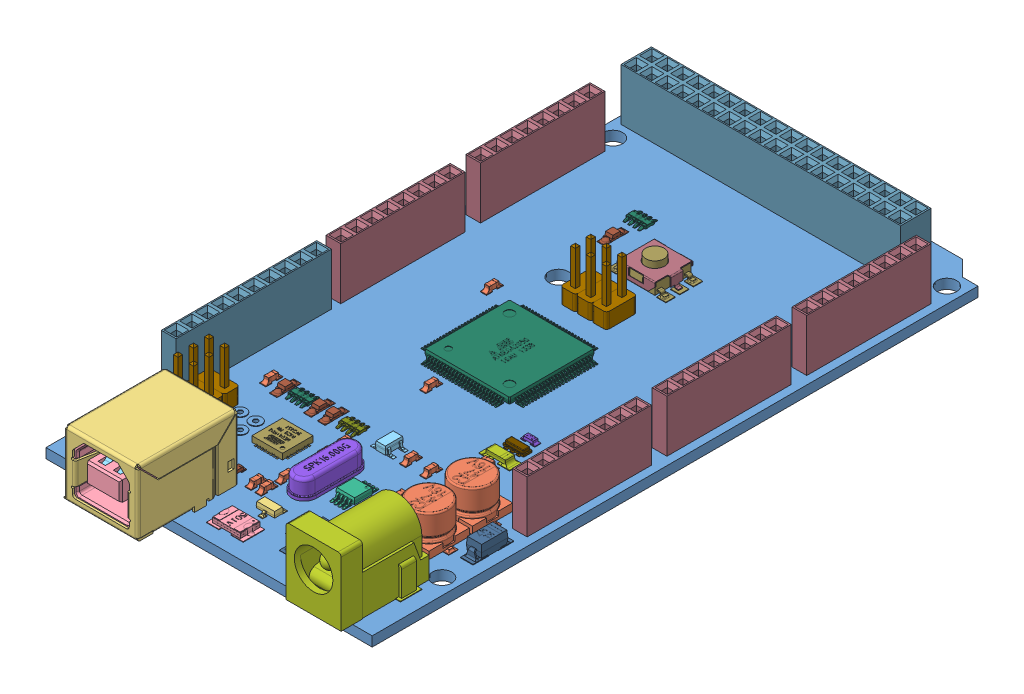
SolidWorks assembly User Library-arduino_MEGA2650-1, configuration Default. Lengths in mm.
Overall size (53.34 15.25 107.95).
67 component instances, 33 part files, 0 mates.
Components (placement in the parent):
- User Library-arduino_MEGA2650-1_MEGAboard-1: User Library-arduino_MEGA2650-1_MEGAboard [Default] at origin size (53.34 1.6 101.6)
- User Library-arduino_MEGA2650-1_47uf CAP Dcase-1: User Library-arduino_MEGA2650-1_47uf CAP Dcase [Default] at (-9.144 0 -18.415) x (0 0 -1) z (1 0 0) size (6.6 5.81 8)
- User Library-arduino_MEGA2650-1_USB SHELL-1: User Library-arduino_MEGA2650-1_USB SHELL [Default] at (-38.02 0.43 6.35) size (13.72 15.2 16.51)
- User Library-arduino_MEGA2650-1_USB core-1: User Library-arduino_MEGA2650-1_USB core [Default] at (-38.02 0.43 6.35) size (11.3 10.68 15.75)
- User Library-arduino_MEGA2650-1_usb top contact-1: User Library-arduino_MEGA2650-1_usb top contact [Default] at (-36.77 6.52 5.97) size (1 9.67 13.76)
- User Library-arduino_MEGA2650-1_usb btm contact-1: User Library-arduino_MEGA2650-1_usb btm contact [Default] at (-36.77 4.84 5.97) size (1 6.84 11.76)
- User Library-arduino_MEGA2650-1_usb btm contact-2: User Library-arduino_MEGA2650-1_usb btm contact [Default] at (-39.27 4.84 5.97) size (1 6.84 11.76)
- User Library-arduino_MEGA2650-1_usb top contact-2: User Library-arduino_MEGA2650-1_usb top contact [Default] at (-39.27 6.52 5.97) size (1 9.67 13.76)
- User Library-arduino_MEGA2650-1_power jack-1: User Library-arduino_MEGA2650-1_power jack [Default] at (-7.675 0 1.905) size (11.2 15.2 15.9)
- User Library-arduino_MEGA2650-1_47uf CAP Dcase-2: User Library-arduino_MEGA2650-1_47uf CAP Dcase [Default] at (-9.144 0 -25.527) x (0 0 -1) z (1 0 0) size (6.6 5.81 8)
- User Library-arduino_MEGA2650-1_crystal-1: User Library-arduino_MEGA2650-1_crystal [Default] at (-26.035 0 -18.415) x (1 0 0) z (0 0 -1) size (4 5 11)
- User Library-arduino_MEGA2650-1_2pin_header__02-1: User Library-arduino_MEGA2650-1_2pin_header__02 [Default] at (-46.23 0 -15.75) size (5 11.75 2.54)
- User Library-arduino_MEGA2650-1_reg-1: User Library-arduino_MEGA2650-1_reg [Default] at (-17.78 0 -8.636) size (6.5 1.69 8.3)
- User Library-arduino_MEGA2650-1_led-1: User Library-arduino_MEGA2650-1_led [Default] at (-34.29 0 -27.94) x (0 0 1) z (-1 0 0) size (4 0.9 1.55)
- User Library-arduino_MEGA2650-1_2pin_header__02-2: User Library-arduino_MEGA2650-1_2pin_header__02 [Default] at (-30.43 0 -64.91) x (0 0 1) z (-1 0 0) size (5 11.75 2.54)
- User Library-arduino_MEGA2650-1_2pin_header__02-3: User Library-arduino_MEGA2650-1_2pin_header__02 [Default] at (-27.89 0 -64.91) x (0 0 1) z (-1 0 0) size (5 11.75 2.54)
- User Library-arduino_MEGA2650-1_2pin_header__02-4: User Library-arduino_MEGA2650-1_2pin_header__02 [Default] at (-25.35 0 -64.91) x (0 0 1) z (-1 0 0) size (5 11.75 2.54)
- User Library-arduino_MEGA2650-1_2pin_header__02-5: User Library-arduino_MEGA2650-1_2pin_header__02 [Default] at (-46.23 0 -18.29) size (5 11.75 2.54)
- User Library-arduino_MEGA2650-1_2pin_header__02-6: User Library-arduino_MEGA2650-1_2pin_header__02 [Default] at (-46.23 0 -20.83) size (5 11.75 2.54)
- User Library-arduino_MEGA2650-1_atmega16u2-1: User Library-arduino_MEGA2650-1_atmega16u2 [Default] at (-34.671 0.06 -20) x (1 0 0) z (0 0 -1) size (5.5 1.01 5.5)
- User Library-arduino_MEGA2650-1_led-2: User Library-arduino_MEGA2650-1_led [Default] at (-36.576 0 -27.94) x (0 0 -1) z (1 0 0) size (4 0.9 1.55)
- User Library-arduino_MEGA2650-1_led-3: User Library-arduino_MEGA2650-1_led [Default] at (-42.164 0 -27.94) x (0 0 1) z (-1 0 0) size (4 0.9 1.55)
- User Library-arduino_MEGA2650-1_led-4: User Library-arduino_MEGA2650-1_led [Default] at (-36.83 0 -76.2) x (0 0 1) z (-1 0 0) size (4 0.9 1.55)
- User Library-arduino_MEGA2650-1_8 PORT HEADER-1: User Library-arduino_MEGA2650-1_8 PORT HEADER [Default] at (-50.8 0 -45.72) x (0 0 -1) z (1 0 0) size (20.32 10.51 2.41)
- User Library-arduino_MEGA2650-1_8 PORT HEADER-2: User Library-arduino_MEGA2650-1_8 PORT HEADER [Default] at (-2.54 0 -27.94) x (0 0 -1) z (1 0 0) size (20.32 10.51 2.41)
- User Library-arduino_MEGA2650-1_8 PORT HEADER-3: User Library-arduino_MEGA2650-1_8 PORT HEADER [Default] at (-2.54 0 -50.8) x (0 0 -1) z (1 0 0) size (20.32 10.51 2.41)
- User Library-arduino_MEGA2650-1_10 PORT HEADER-1: User Library-arduino_MEGA2650-1_10 PORT HEADER [Default] at (-50.8 0 -18.796) x (0 0 -1) z (1 0 0) size (25.4 10.51 2.41)
- User Library-arduino_MEGA2650-1_102 RESISTOR PACK-1: User Library-arduino_MEGA2650-1_102 RESISTOR PACK [Default] at (-36.83 0 -80.645) size (3.2 0.51 3)
- User Library-arduino_MEGA2650-1_102 RESISTOR PACK-2: User Library-arduino_MEGA2650-1_102 RESISTOR PACK [Default] at (-39.37 0 -27.94) size (3.2 0.51 3)
- User Library-arduino_MEGA2650-1_103 RESISTOR PACK-1: User Library-arduino_MEGA2650-1_103 RESISTOR PACK [Default] at (-31.115 0 -27.94) size (3.2 0.51 3)
- User Library-arduino_MEGA2650-1_220 RESISTOR PACK-1: User Library-arduino_MEGA2650-1_220 RESISTOR PACK [Default] at (-37.084 0 -12.065) size (3.2 0.51 3)
- User Library-arduino_MEGA2650-1_16mhz crystal - measured-1: User Library-arduino_MEGA2650-1_16mhz crystal - measured [Default] at (-14.605 0 -38.354) size (3.4 0.8 2)
- User Library-arduino_MEGA2650-1_PADS001-1: User Library-arduino_MEGA2650-1_PADS001 [Default] at (-39.878 0.1 -18.288) x (-1 0 0) z (0 0 1) size (4.54 0.1 4.54)
- User Library-arduino_MEGA2650-1_603 cap on pad-1: User Library-arduino_MEGA2650-1_603 cap on pad [Default] at (-44.45 0 -27.94) x (0 0 -1) z (1 0 0) size (2.76 0.91 1.02)
- User Library-arduino_MEGA2650-1_ssot3-1: User Library-arduino_MEGA2650-1_ssot3 [Default] at (-25.908 0 -9.144) x (-1 0 0) z (0 0 -1) size (3 1.13 3.09)
- User Library-arduino_MEGA2650-1_mf-msmf050-2-1: User Library-arduino_MEGA2650-1_mf-msmf050-2 [Default] at (-26.67 0 -4.445) size (5.76 1.02 3.72)
- User Library-arduino_MEGA2650-1_603 cap on pad-2: User Library-arduino_MEGA2650-1_603 cap on pad [Default] at (-29.337 0 -24.765) x (0 0 1) z (-1 0 0) size (2.76 0.91 1.02)
- User Library-arduino_MEGA2650-1_603 cap on pad-3: User Library-arduino_MEGA2650-1_603 cap on pad [Default] at (-30.988 0 -12.065) x (0 0 -1) z (1 0 0) size (2.76 0.91 1.02)
- User Library-arduino_MEGA2650-1_lmv358-1: User Library-arduino_MEGA2650-1_lmv358 [Default] at (-25.146 0 -27.94) size (3.7 1.4 2.9)
- User Library-arduino_MEGA2650-1_603 cap on pad-4: User Library-arduino_MEGA2650-1_603 cap on pad [Default] at (-17.653 0 -14.351) size (2.76 0.91 1.02)
- User Library-arduino_MEGA2650-1_603 cap on pad-5: User Library-arduino_MEGA2650-1_603 cap on pad [Default] at (-29.337 0 -12.065) x (0 0 1) z (-1 0 0) size (2.76 0.91 1.02)
- User Library-arduino_MEGA2650-1_603 cap on pad-6: User Library-arduino_MEGA2650-1_603 cap on pad [Default] at (-29.337 0 -21.59) x (0 0 1) z (-1 0 0) size (2.76 0.91 1.02)
- User Library-arduino_MEGA2650-1_603 cap on pad-7: User Library-arduino_MEGA2650-1_603 cap on pad [Default] at (-29.337 0 -15.24) x (0 0 1) z (-1 0 0) size (2.76 0.91 1.02)
- User Library-arduino_MEGA2650-1_603 cap on pad-8: User Library-arduino_MEGA2650-1_603 cap on pad [Default] at (-42.291 0 -12.065) x (0 0 1) z (-1 0 0) size (2.76 0.91 1.02)
- User Library-arduino_MEGA2650-1_lp2985dgkr-1: User Library-arduino_MEGA2650-1_lp2985dgkr [Default] at (-21.336 0 -18.415) x (0 0 -1) z (1 0 0) size (5.85 1.1 3)
- User Library-arduino_MEGA2650-1_cd1206 diode-1: User Library-arduino_MEGA2650-1_cd1206 diode [Default] at (-14.605 0 -35.56) x (0 0 1) z (-1 0 0) size (2.09 0.96 5)
- User Library-arduino_MEGA2650-1_cd1206 diode-2: User Library-arduino_MEGA2650-1_cd1206 diode [Default] at (-46.228 0 -13.081) x (0 0 1) z (-1 0 0) size (2.09 0.96 5)
- User Library-arduino_MEGA2650-1_603 resistor-1: User Library-arduino_MEGA2650-1_603 resistor [Default] at (-29.337 0 -18.415) x (0 0 1) z (-1 0 0) size (2.36 0.62 1.03)
- User Library-arduino_MEGA2650-1_blm21-1: User Library-arduino_MEGA2650-1_blm21 [Default] at (-45.085 0 -8.255) x (0 0 -1) z (1 0 0) size (2.78 0.95 1.32)
- User Library-arduino_MEGA2650-1_m7 diode-1: User Library-arduino_MEGA2650-1_m7 diode [Default] at (-2.794 0 -21.59) x (0 0 -1) z (1 0 0) size (6.66 2.35 2.5)
- User Library-arduino_MEGA2650-1_MLC0603-1: User Library-arduino_MEGA2650-1_MLC0603 [Default] at (-34.29 0 -12.065) x (0 0 -1) z (1 0 0) size (2.36 0.6 1.03)
- User Library-arduino_MEGA2650-1_MLC0603-2: User Library-arduino_MEGA2650-1_MLC0603 [Default] at (-39.878 0 -12.065) x (0 0 -1) z (1 0 0) size (2.36 0.6 1.03)
- User Library-arduino_MEGA2650-1_RESET CORE-1: User Library-arduino_MEGA2650-1_RESET CORE [Default] at (-27.94 0.1 -74.168) x (0 0 1) z (-1 0 0) size (6.2 3.1 9.6)
- User Library-arduino_MEGA2650-1_RESET-1: User Library-arduino_MEGA2650-1_RESET [Default] at (-27.94 0.1 -74.168) size (7.3 2 6.2)
- User Library-arduino_MEGA2650-1_8 PORT HEADER-4: User Library-arduino_MEGA2650-1_8 PORT HEADER [Default] at (-2.54 0 -73.66) x (0 0 -1) z (1 0 0) size (20.32 10.51 2.41)
- User Library-arduino_MEGA2650-1_8 PORT HEADER-5: User Library-arduino_MEGA2650-1_8 PORT HEADER [Default] at (-50.8 0 -68.58) x (0 0 -1) z (1 0 0) size (20.32 10.51 2.41)
- User Library-arduino_MEGA2650-1_603 cap on pad-9: User Library-arduino_MEGA2650-1_603 cap on pad [Default] at (-21.59 0 -27.94) x (0 0 1) z (-1 0 0) size (2.76 0.91 1.02)
- User Library-arduino_MEGA2650-1_603 cap on pad-10: User Library-arduino_MEGA2650-1_603 cap on pad [Default] at (-18.288 0 -27.94) x (0 0 1) z (-1 0 0) size (2.76 0.91 1.02)
- User Library-arduino_MEGA2650-1_103 RESISTOR PACK-2: User Library-arduino_MEGA2650-1_103 RESISTOR PACK [Default] at (-16.51 0 -18.415) size (3.2 0.51 3)
- User Library-arduino_MEGA2650-1_603 cap on pad-11: User Library-arduino_MEGA2650-1_603 cap on pad [Default] at (-17.145 0 -21.59) x (0 0 -1) z (1 0 0) size (2.76 0.91 1.02)
- User Library-arduino_MEGA2650-1_603 cap on pad-12: User Library-arduino_MEGA2650-1_603 cap on pad [Default] at (-39.37 0 -58.928) x (0 0 1) z (-1 0 0) size (2.76 0.91 1.02)
- User Library-arduino_MEGA2650-1_603 cap on pad-13: User Library-arduino_MEGA2650-1_603 cap on pad [Default] at (-14.605 0 -33.528) size (2.76 0.91 1.02)
- User Library-arduino_MEGA2650-1_603 resistor-2: User Library-arduino_MEGA2650-1_603 resistor [Default] at (-14.605 0 -40.513) x (-1 0 0) z (0 0 -1) size (2.36 0.62 1.03)
- User Library-arduino_MEGA2650-1_603 cap on pad-14: User Library-arduino_MEGA2650-1_603 cap on pad [Default] at (-7.112 0 -38.608) x (0 0 1) z (-1 0 0) size (2.76 0.91 1.02)
- User Library-arduino_MEGA2650-1_603 cap on pad-15: User Library-arduino_MEGA2650-1_603 cap on pad [Default] at (-30.4038 0 -40.0558) x (0 0 1) z (-1 0 0) size (2.76 0.91 1.02)
- User Library-arduino_MEGA2650-1_18 X 2 ROW HEADER-1: User Library-arduino_MEGA2650-1_18 X 2 ROW HEADER [Default] at (-50.8 0 -95.25) size (45.72 10.51 4.95)
- User Library-arduino_MEGA2650-1_atmega2650-16AU-1: User Library-arduino_MEGA2650-1_atmega2650-16AU [Default] at (-28.3464 0.1 -50.8) x (0 0 1) z (-1 0 0) size (16.8 1.11 16.8)
